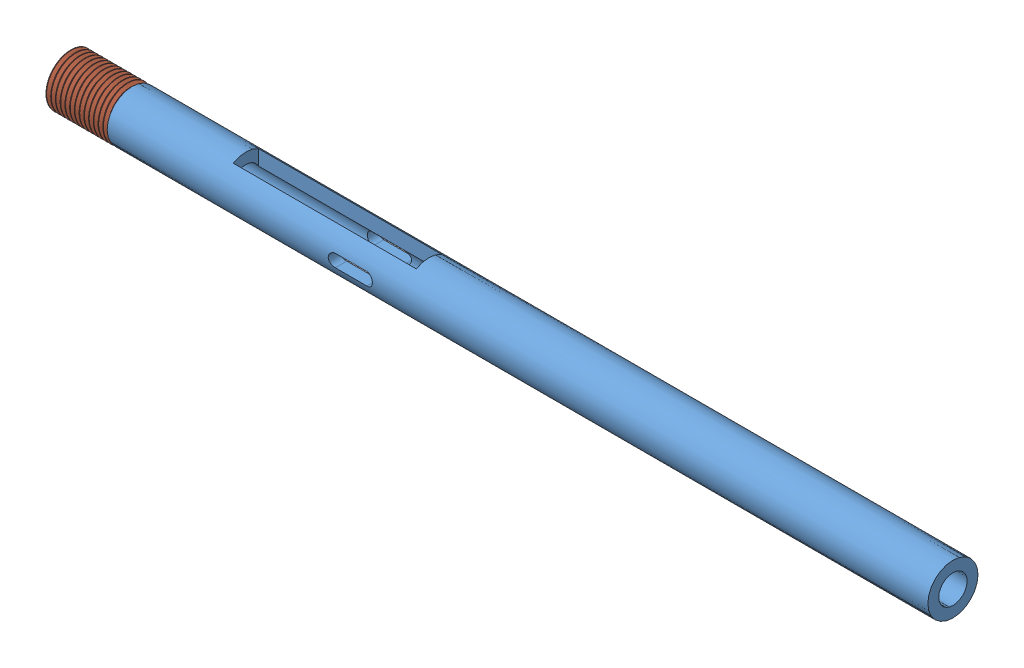
SolidWorks assembly slider handle assembly v-5 22-Nov-2017, configuration Default. Lengths in mm.
Overall size (140.35 13 13).
2 component instances, 2 part files, 2 mates.
Components (placement in the parent):
- wheel_handle_body_slider v-4 06-Nov-2017-1: wheel_handle_body_slider v-4 06-Nov-2017 [Default] at (-10.0168 48.9172 77.5775) size (130 7.94 7.94)
- M8X0.75-1: M8X0.75 [91290A414] at (-10.0168 48.9172 77.5775) x (0 0 -1) z (1 0 0) size (13 13 10.51)
Mates (geometry in assembly coordinates):
- Coincident1: coincident anti-aligned: plane of wheel_handle_body_slider v-4 06-Nov-2017-1 through (-10.0168 48.9172 77.5775) normal (-1 0 0); plane of M8X0.75-1 through (-10.0168 48.9172 77.5775) normal (1 0 0)
- Concentric1: concentric anti-aligned: circle of wheel_handle_body_slider v-4 06-Nov-2017-1; circle of M8X0.75-1
